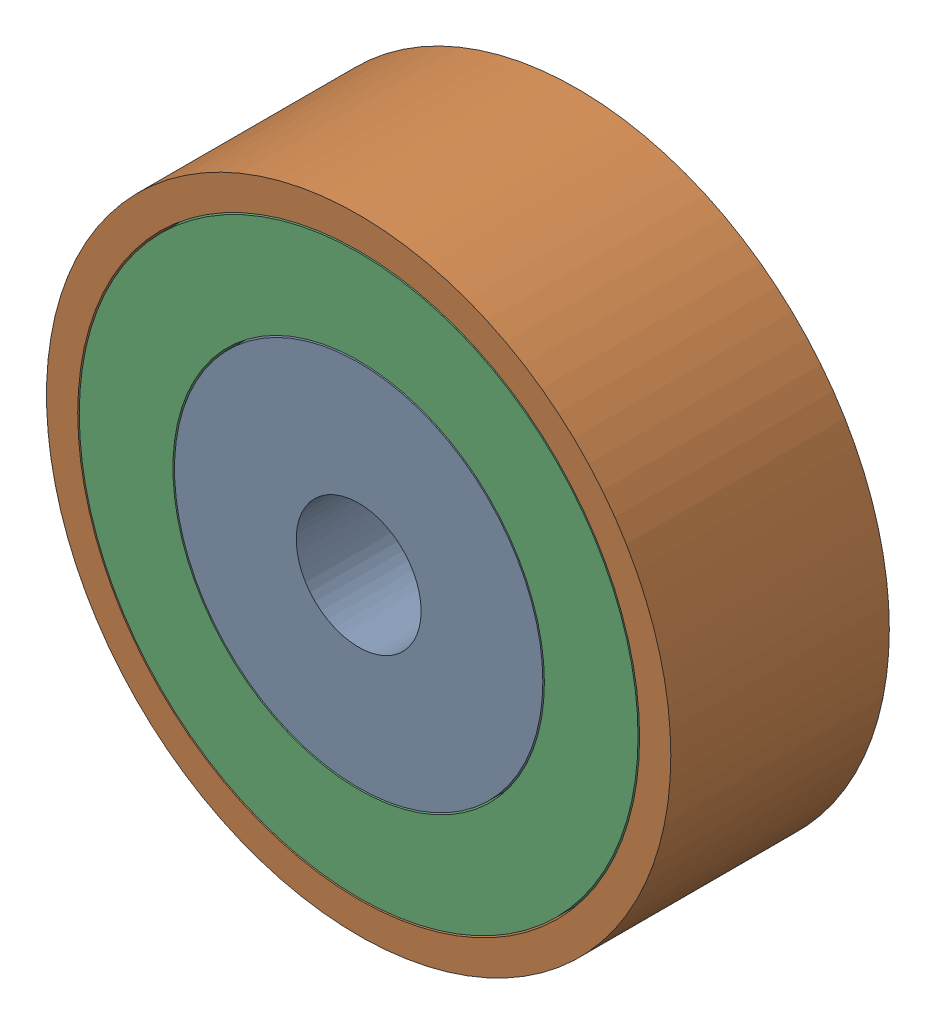
SolidWorks assembly 镜向轴承11, configuration 默认. Lengths in mm.
Overall size (20 20 7).
3 component instances, 3 part files, 4 mates.
Components (placement in the parent):
- 镜向轴承内圈-1: 镜向轴承内圈 [默认] at (-5.0655 0.8032 -6.5) size (11.8 11.8 7)
- 镜向轴承外圈-1: 镜向轴承外圈 [默认] at (-5.0655 0.8032 -6.5) size (20 20 7)
- 镜向轴承中圈-1: 镜向轴承中圈 [默认] at (-5.0655 0.8032 -6.5) size (17.9 17.9 7)
Mates (geometry in assembly coordinates):
- 重合1: coincident: plane of ? through (-5.0655 0.8032 -13.5) normal (0 0 -1); plane of ? through (-5.0655 0.8032 -13.5) normal (0 0 -1)
- 重合2: coincident: plane of ? through (-5.0655 0.8032 -13.5) normal (0 0 -1); plane of ? through (-5.0655 0.8032 -13.5) normal (0 0 -1)
- 同心1: concentric: cylinder of ? through (-5.0655 0.8032 -13.5) axis (0 0 1) radius 9; cylinder of ? through (-5.0655 0.8032 -13.5) axis (0 0 1) radius 8.95
- 同心2: concentric: cylinder of ? through (-5.0655 0.8032 -13.5) axis (0 0 1) radius 5.9; cylinder of ? through (-5.0655 0.8032 -13.5) axis (0 0 1) radius 5.95
